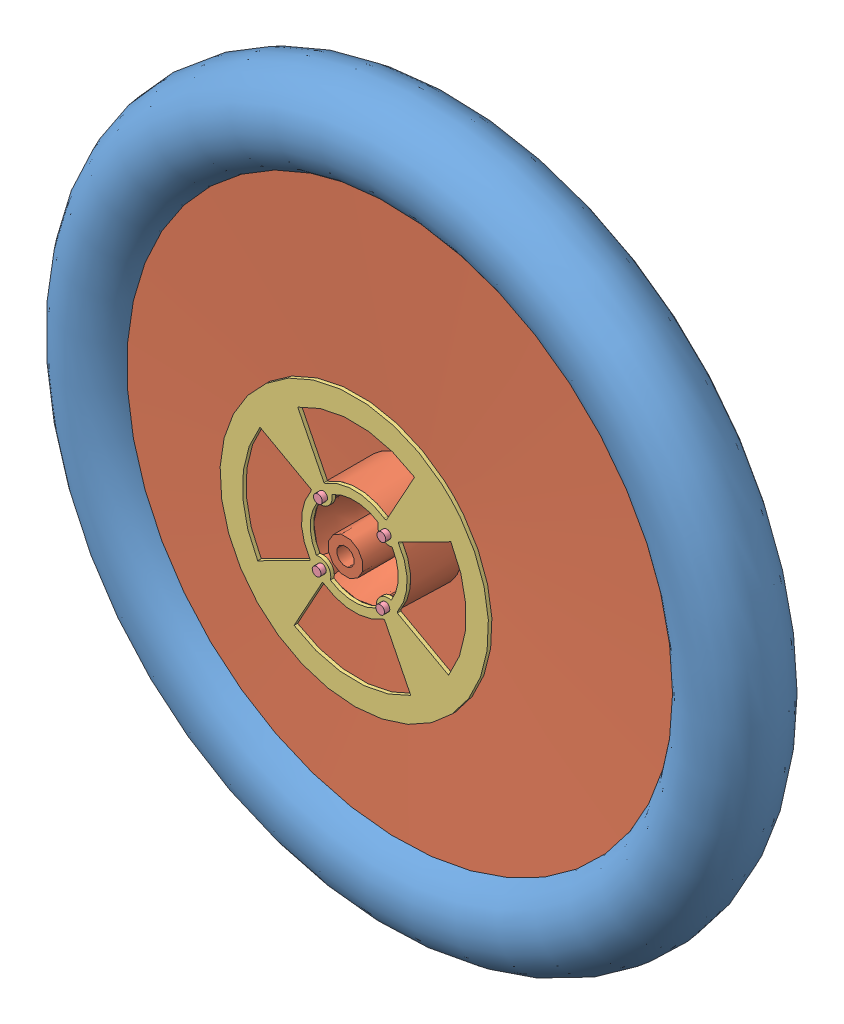
SolidWorks assembly reifen, configuration Standard. Lengths in mm.
Overall size (497.77 497.77 68.17).
7 component instances, 4 part files, 14 mates.
Components (placement in the parent):
- reifen-1: reifen [Standard] at (-11.8699 -6.6958 62.5) size (405.6 405.6 50)
- felge-1: felge [Standard] at (-11.8699 -6.6958 62.5) x (-0.693049 0.72089 0) z (0 0 1) size (352.04 352.04 55.54)
- scheibe-1: scheibe [Standard] at (-11.8699 -6.6958 100.6706) x (0 0 -1) z (-0.72089 -0.693049 0) size (2 152.4 152.4)
- 20_M3_imbus-1: 20_M3_imbus [Standard] at (11.7742 16.1815 100.6706) x (0.923728 0.383049 0) z (0 0 -1) size (5 5 23)
- 20_M3_imbus-2: 20_M3_imbus [Standard] at (0.5415 -30.2831 100.6706) x (-0.923728 -0.383049 0) z (0 0 -1) size (5 5 23)
- 20_M3_imbus-3: 20_M3_imbus [Standard] at (-24.2813 16.8914 100.6706) x (0.923728 0.383049 0) z (0 0 -1) size (5 5 23)
- 20_M3_imbus-4: 20_M3_imbus [Standard] at (-36.1718 -28.8107 100.6706) x (-0.967177 -0.254104 0) z (0 0 -1) size (5 5 23)
Mates (geometry in assembly coordinates):
- Rotationsmotor2: unknown: edge_curve of reifen-1; unknown of reifen-1
- Deckungsgleich2: coincident aligned: axis of reifen-1; axis of felge-1
- Deckungsgleich3: coincident aligned: plane of reifen-1 through (-11.8699 -6.6958 62.5) normal (0 0 1); plane of felge-1 through (-11.8699 -6.6958 62.5) normal (0 0 1)
- Deckungsgleich4: coincident anti-aligned: axis of reifen-1; axis of scheibe-1
- Konzentrisch4: concentric anti-aligned: circle of felge-1 centre (6.5128 10.9769 98.6706) axis (0 0 1); circle of scheibe-1 centre (6.5128 10.9769 100.6706) axis (0 0 -1)
- Deckungsgleich5: coincident anti-aligned: plane of felge-1 through (-33.4966 -27.4873 98.6706) normal (0 0 1); plane of scheibe-1 through (-11.8699 -6.6958 98.6706) normal (0 0 -1)
- Deckungsgleich6: coincident: point of felge-1; axis of 20_M3_imbus-4
- Deckungsgleich7: coincident anti-aligned: plane of scheibe-1 through (-11.8699 -6.6958 100.6706) normal (0 0 1); plane of 20_M3_imbus-4 through (-30.2526 -24.3686 100.6706) normal (0 0 -1)
- Deckungsgleich8: coincident: point of felge-1; axis of 20_M3_imbus-2
- Deckungsgleich9: coincident: point of felge-1; axis of 20_M3_imbus-1
- Deckungsgleich10: coincident: point of felge-1; axis of 20_M3_imbus-3
- Deckungsgleich11: coincident anti-aligned: plane of scheibe-1 through (-11.8699 -6.6958 100.6706) normal (0 0 1); plane of 20_M3_imbus-1 through (6.5128 10.9769 100.6706) normal (0 0 -1)
- Deckungsgleich12: coincident anti-aligned: plane of scheibe-1 through (-11.8699 -6.6958 100.6706) normal (0 0 1); plane of 20_M3_imbus-3 through (-29.5426 11.6869 100.6706) normal (0 0 -1)
- Deckungsgleich13: coincident aligned: plane of scheibe-1 through (-11.8699 -6.6958 100.6706) normal (0 0 1); circle of 20_M3_imbus-2 centre (5.8029 -25.0785 100.6706) axis (0 0 1)
